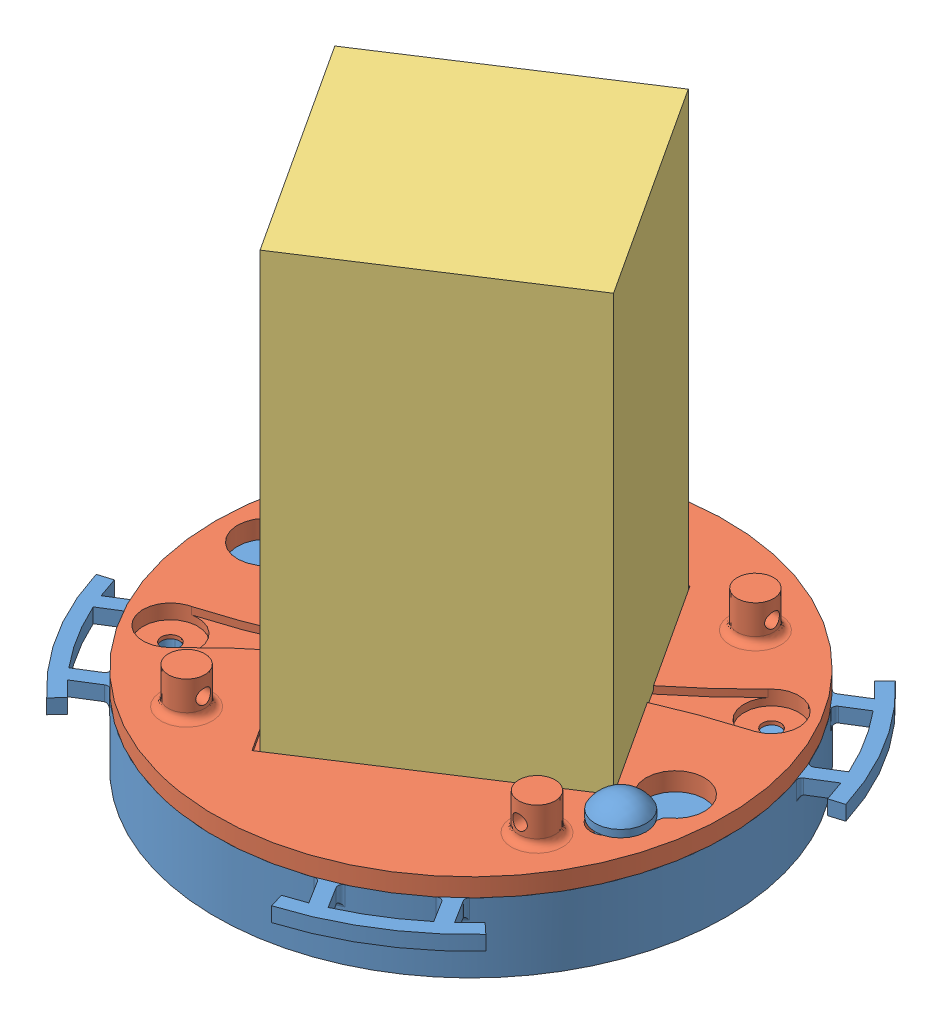
SolidWorks assembly Humming feeder, configuration Default. Lengths in mm.
Overall size (210.73 187.96 210.73).
3 component instances, 3 part files, 5 mates.
Components (placement in the parent):
- Feeder Base-1: Feeder Base [Simplified] at (301.9191 -25.3608 3.2192) size (199.8 44.7 199.8)
- Feeder Cover-1: Feeder Cover [Default] at (-2.8809 5.1192 3.2192) x (0.978376 0 0.206834) z (-0.206834 0 0.978376) size (177.8 19.05 177.8)
- electronic box-1: electronic box [Default] at (-1.4751 10.1992 3.5164) x (0.83807 0 -0.545563) z (0.545563 0 0.83807) size (88.9 152.4 88.9)
Mates (geometry in assembly coordinates):
- Concentric1: concentric aligned: cylinder of Feeder Base-1 through (-2.8809 -25.3608 3.2192) axis (0 -1 0) radius 88.9; cylinder of Feeder Cover-1 through (-2.8809 11.4692 3.2192) axis (0 -1 0) radius 88.9
- Coincident1: coincident anti-aligned: plane of Feeder Base-1 through (80.9391 5.1192 3.2192) normal (0 1 0); plane of Feeder Cover-1 through (-2.8809 5.1192 3.2192) normal (0 -1 0)
- Coincident2: coincident anti-aligned: plane of Feeder Cover-1 through (-2.8809 10.1992 3.2192) normal (0 1 0); plane of electronic box-1 through (-1.4751 10.1992 3.5164) normal (0 -1 0)
- Coincident3: coincident anti-aligned: plane of Feeder Cover-1 through (-16.18 10.1992 66.1275) normal (-0.545563 0 -0.83807); plane of electronic box-1 through (60.0274 162.5992 16.5184) normal (0.545563 0 0.83807)
- Coincident4: coincident anti-aligned: plane of Feeder Cover-1 through (60.0274 10.1992 16.5184) normal (-0.83807 0 0.545563); plane of electronic box-1 through (60.0274 162.5992 16.5184) normal (0.83807 0 -0.545563)
